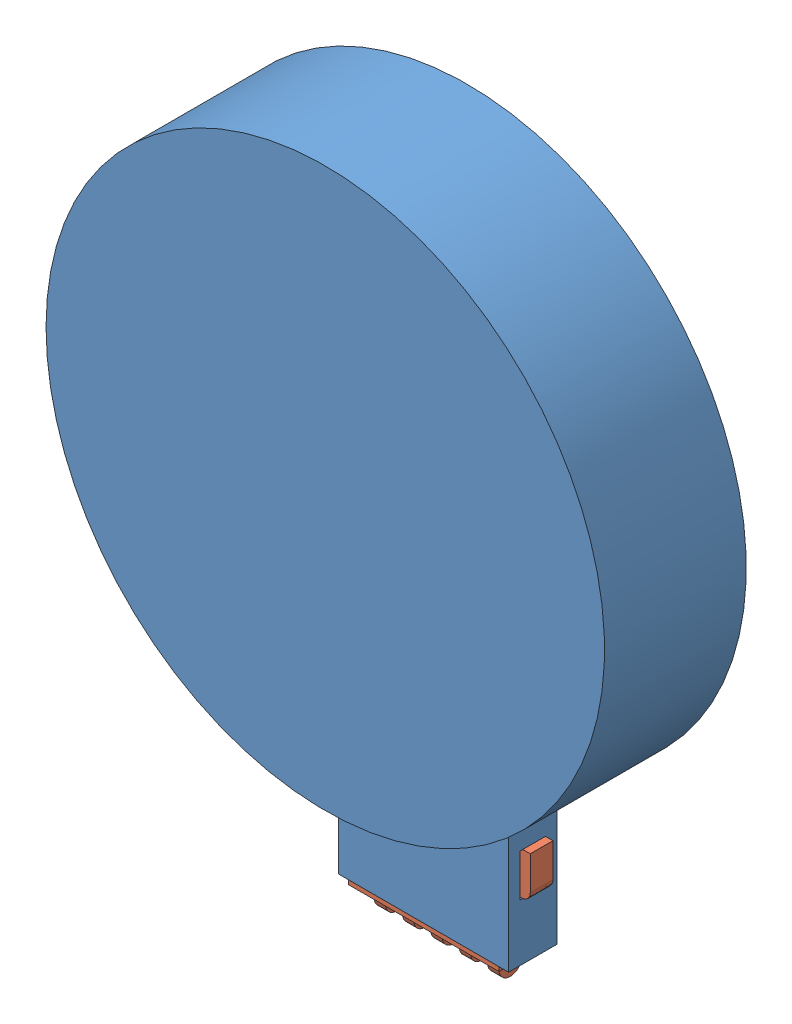
SolidWorks assembly JointDesign_v2_Assem, configuration Default. Lengths in mm.
Overall size (197.01 257.01 50.5).
2 component instances, 2 part files, 2 mates.
Components (placement in the parent):
- JointDesign_v2_P1-1: JointDesign_v2_P1 [Default] at (100.1291 194.6056 140.7823) size (197.01 247.01 50)
- JointDesign_v2_P2-1: JointDesign_v2_P2 [Default] at (101.3833 44.1002 148.7823) size (66.11 45 17)
Mates (geometry in assembly coordinates):
- Coincident1: coincident anti-aligned: plane of JointDesign_v2_P1-1 through (198.6345 66.1002 144.7823) normal (0 1 0); plane of JointDesign_v2_P2-1 through (134.4377 66.1002 152.7823) normal (0 -1 0)
- Coincident2: coincident anti-aligned: plane of JointDesign_v2_P1-1 through (198.6345 81.1002 144.7823) normal (0 0 1); plane of JointDesign_v2_P2-1 through (79.3833 49.1002 144.7823) normal (0 0 -1)
